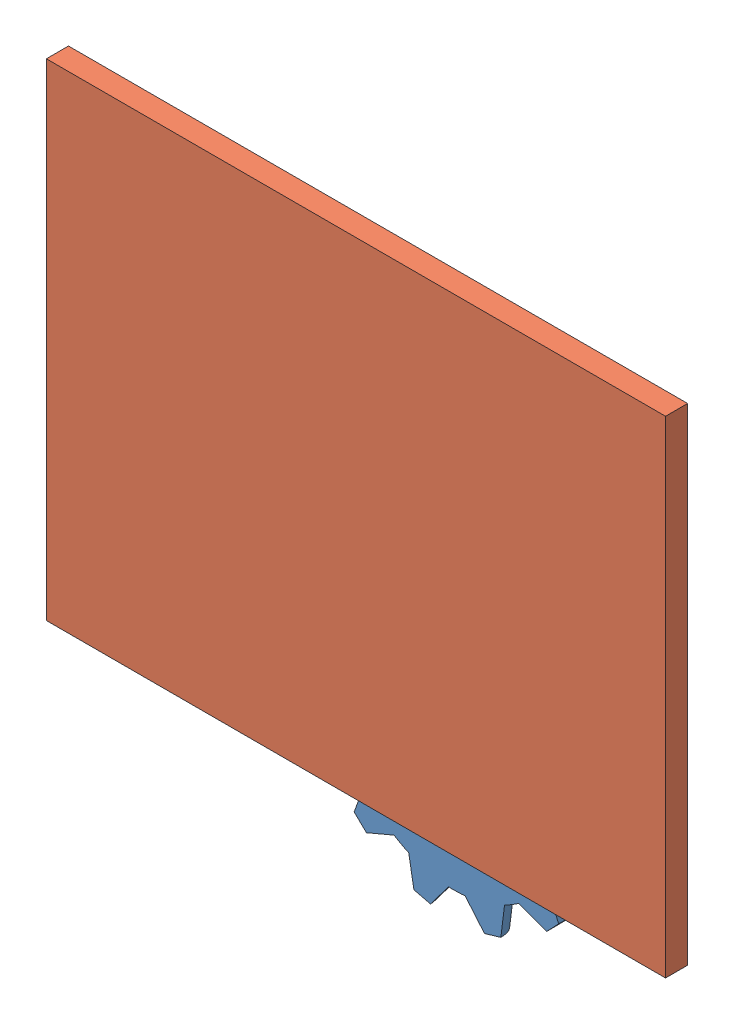
SolidWorks assembly Test_5_Working, configuration Default. Lengths in mm.
Overall size (285.47 269.91 20.61).
3 component instances, 2 part files, 7 mates.
Components (placement in the parent):
- Gear_2-3: Gear_2 [Default] at (-105.6577 26.5914 -10) x (0.958794 0.284101 0) z (0 0 1) size (123.1 123.1 10)
- Gear_2-4: Gear_2 [Default] at (-213.1724 71.5073 -10) x (0.193443 -0.981111 0) z (0 0 1) size (123.1 123.1 10)
- Background-1: Background [Default] at (-164.4985 122.0365 0) size (280 220 10)
Mates (geometry in assembly coordinates):
- Concentric1: concentric: circle of Gear_1-4
- Concentric2: concentric: circle of Gear_1-3
- Coincident3: coincident: plane of assembly through (0 0 0) normal (0 0 1); plane of Background-1 through (-164.4985 122.0365 0) normal (0 0 -1); plane of assembly
- Coincident4: coincident: plane of assembly through (0 0 0) normal (1 0 0); plane of Background-1 through (0 220 10) normal (1 0 0); plane of assembly
- Coincident5: coincident: plane of assembly through (0 0 0) normal (0 1 0); plane of Background-1 through (-280 0 10) normal (0 -1 0); plane of assembly
- Coincident6: coincident anti-aligned: plane of Gear_1-4 through (-213.1724 71.5073 0) normal (0 0 1); plane of Background-1 through (-164.4985 122.0365 0) normal (0 0 -1)
- Coincident7: coincident anti-aligned: plane of Gear_1-3 through (-105.6577 26.5914 0) normal (0 0 1); plane of Background-1 through (-164.4985 122.0365 0) normal (0 0 -1)
